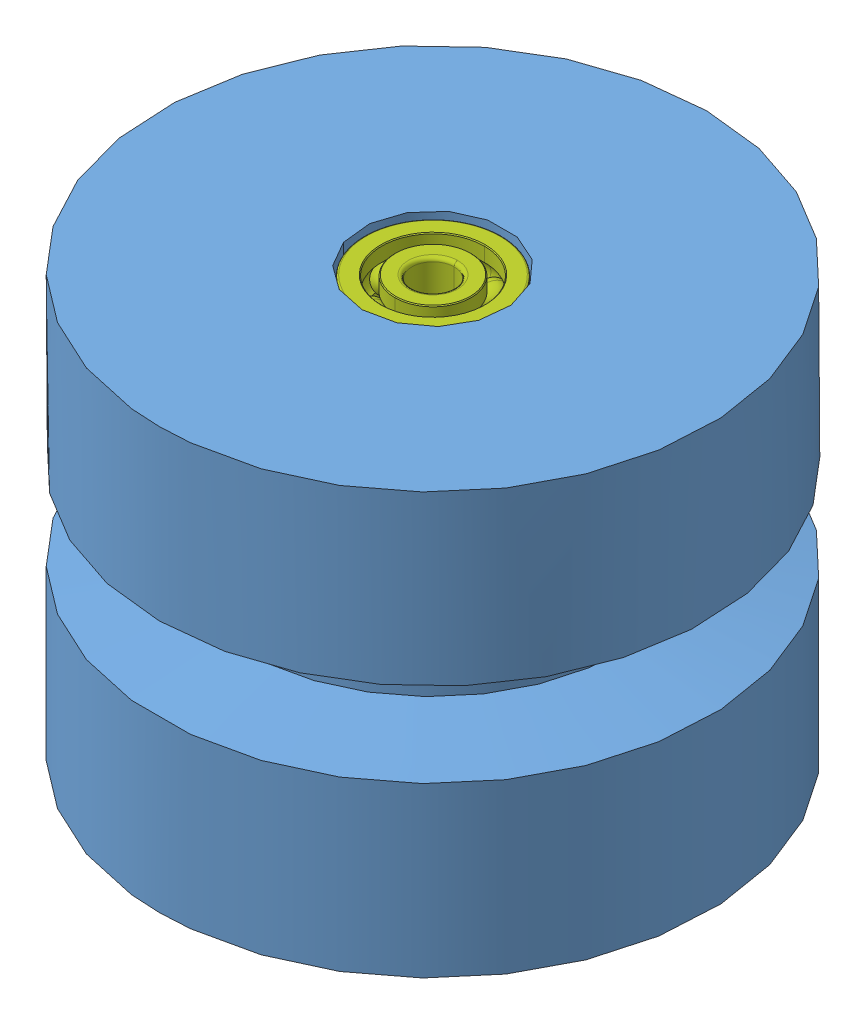
SolidWorks assembly Runner_Wheel_Bearing_Assembly, configuration Default. Lengths in mm.
Overall size (52 40 52).
17 component instances, 7 part files, 4 mates.
Components (placement in the parent):
- Runner_Wheel-1: Runner_Wheel [Default] at (19.3107 7.5629 39.6772) size (52 40 52)
- Ball_Bearing_608_2RSH-1: Ball_Bearing_608_2RSH [Default] at (19.3107 11.5629 39.6772) x (0.810649 0 -0.585532) z (0.585532 0 0.810649) size (25.49 7.53 25.49)
  - Deep Groove Ball Bearing 608-2RSH 8mm I.D, 22mm O.D.stp-1: Deep Groove Ball Bearing 608-2RSH 8mm I.D, 22mm O.D.stp [Default] at origin size (25.49 7.53 25.49)
    - outer race.stp-1: outer race.stp [Default] at origin size (22 7 22)
    - inner race.stp-1: inner race.stp [Default] x (0.998045 0 -0.0625) z (0.0625 0 0.998045) size (12 7 12)
    - retainer.stp-1: retainer.stp [Default] x (-0.325178 0 -0.945653) z (-0.945653 0 0.325178) size (20.06 6 20.06)
    - ball.stp-1: ball.stp [Default] at (-6.7396 0 -3.2906) x (-0.584318 0.768334 -0.261218) z (-0.624567 -0.631294 -0.459765) size (5 5 5)
    - ball.stp-2: ball.stp [Default] at (3.2906 0 -6.7396) x (-0.938425 0.011388 -0.345297) z (0.106265 -0.94149 -0.319851) size (5 5 5)
    - ball.stp-3: ball.stp [Default] at (-2.4388 0 -7.0924) x (-0.938425 0.011388 -0.345297) z (0.106265 -0.94149 -0.319851) size (5 5 5)
    - ball.stp-4: ball.stp [Default] at (7.0924 0 -2.4388) x (-0.938425 0.011388 -0.345297) z (0.106265 -0.94149 -0.319851) size (5 5 5)
    - ball.stp-5: ball.stp [Default] at (-7.0924 0 2.4388) x (-0.938425 0.011388 -0.345297) z (0.106265 -0.94149 -0.319851) size (5 5 5)
    - ball.stp-6: ball.stp [Default] at (-3.2906 0 6.7396) x (-0.938425 0.011388 -0.345297) z (0.106265 -0.94149 -0.319851) size (5 5 5)
    - ball.stp-7: ball.stp [Default] at (2.4388 0 7.0924) x (-0.938425 0.011388 -0.345297) z (0.106265 -0.94149 -0.319851) size (5 5 5)
    - ball.stp-8: ball.stp [Default] at (6.7396 0 3.2906) x (-0.938425 0.011388 -0.345297) z (0.106265 -0.94149 -0.319851) size (5 5 5)
    - cover.stp-1: cover.stp [Default] at (0 -3.25 0) x (0.969563 0 0.244841) z (-0.244841 0 0.969563) size (18 0.57 18)
    - cover.stp-2: cover.stp [Default] at (0 3.25 0) x (-0.15753 0 -0.987514) z (-0.987514 0 0.15753) size (18 0.57 18)
- 624_Bearing-1: 624_Bearing [Default] at (19.3107 42.0629 39.6772) x (0 -1 0) z (0 0 -1) size (5 13 13)
Mates (geometry in assembly coordinates):
- Concentric1: concentric anti-aligned: cylinder of Runner_Wheel-1 through (19.3107 15.0629 39.6772) axis (0 -1 0) radius 11.25; cylinder of Ball_Bearing_608_2RSH-1/Deep Groove Ball Bearing 608-2RSH 8mm I.D, 22mm O.D.stp-1/inner race.stp-1 through (19.3107 8.0629 39.6772) axis (0 1 0) radius 4
- Coincident1: coincident anti-aligned: plane of Runner_Wheel-1 through (19.3107 15.0629 39.6772) normal (0 -1 0); plane of Ball_Bearing_608_2RSH-1/Deep Groove Ball Bearing 608-2RSH 8mm I.D, 22mm O.D.stp-1/outer race.stp-1 through (19.3107 15.0629 39.6772) normal (0 1 0)
- Concentric2: concentric anti-aligned: cylinder of Runner_Wheel-1 through (19.3107 7.5629 39.6772) axis (0 1 0) radius 2; cylinder of 624_Bearing-1 through (19.3107 42.0629 39.6772) axis (0 -1 0) radius 2
- Coincident2: coincident anti-aligned: plane of Runner_Wheel-1 through (19.3107 42.0629 39.6772) normal (0 1 0); plane of 624_Bearing-1 through (14.3557 42.0629 39.6772) normal (0 -1 0)
